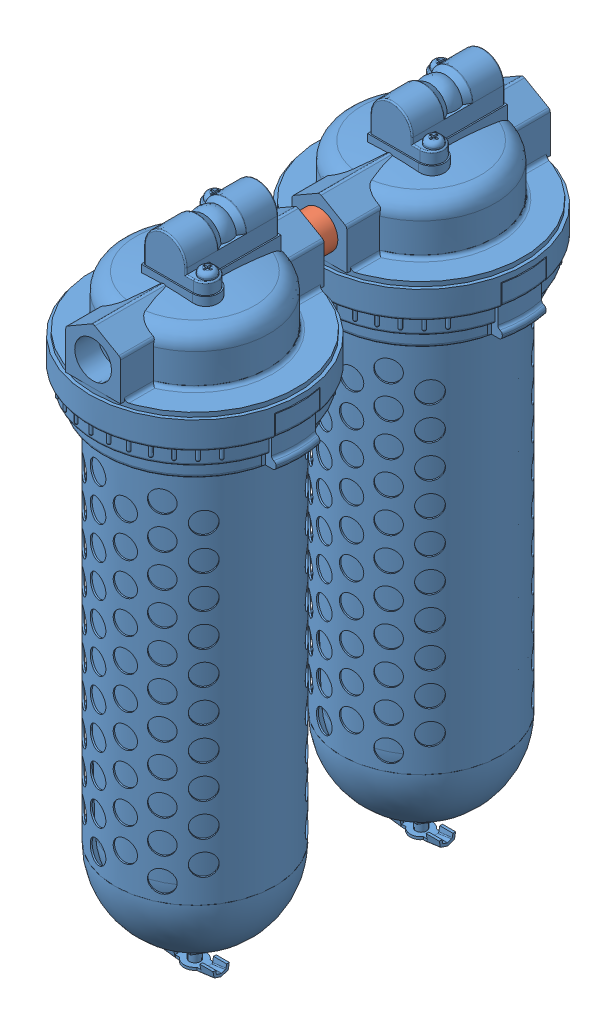
SolidWorks assembly ReadingTech_4P-150-P04-DCPi, configuration Default. Lengths in mm.
Overall size (121.86 375.27 252.73).
3 component instances, 2 part files, 3 mates.
Components (placement in the parent):
- ReadingTech_3P-150-P04-Pi-1: ReadingTech_3P-150-P04-Pi [Default] at (-27.4063 -223.0194 2.5571) size (121.86 375.27 121.67)
- ReadingTech_3P-150-P04-Pi-2: ReadingTech_3P-150-P04-Pi [Default] at (-27.4063 -223.0194 -128.5069) size (121.86 375.27 121.67)
- ReadingTech- 90,150cfm_connector_.5in-1: ReadingTech- 90,150cfm_connector_.5in [Default] at (-27.4063 161.9176 -56.3709) x (1 0 0) z (0 1 0) size (21.34 13.21 21.34)
Mates (geometry in assembly coordinates):
- Coincident1: coincident anti-aligned: circle of ReadingTech_3P-150-P04-Pi-2; circle of ReadingTech- 90,150cfm_connector_.5in-1
- Coincident2: coincident aligned: circle of ReadingTech_3P-150-P04-Pi-1; circle of ReadingTech- 90,150cfm_connector_.5in-1
- Coincident3: coincident aligned: plane of ReadingTech_3P-150-P04-Pi-1 through (-11.5313 170.8076 61.4851) normal (1 0 0); plane of ReadingTech_3P-150-P04-Pi-2 through (-11.5313 170.8076 -69.5789) normal (1 0 0)
